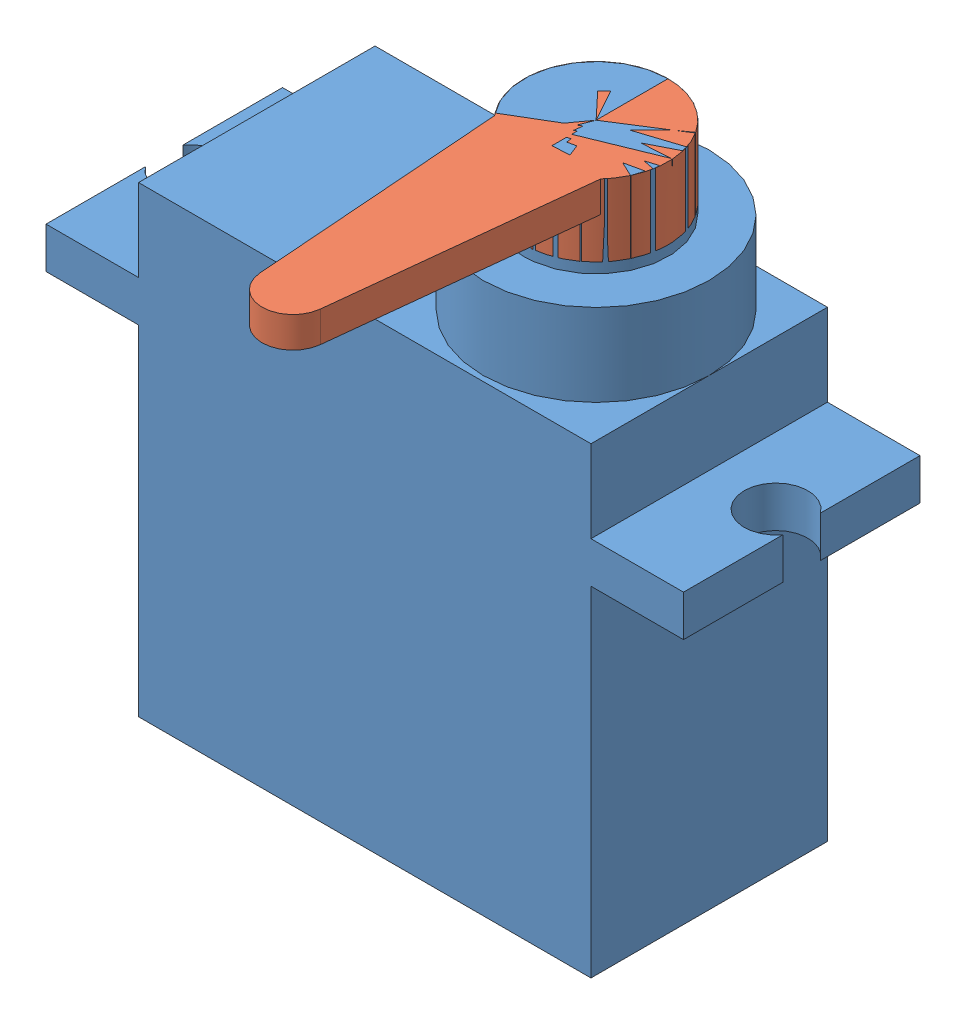
SolidWorks assembly Servo_s, configuration Default. Lengths in mm.
Overall size (31 30.5 21.81).
2 component instances, 2 part files, 2 mates.
Components (placement in the parent):
- Servo_s_Body-1: Servo_s_Body [Default] at (14.7396 6.0253 18.66) size (31 30.5 11.5)
- Servo_s_Wing-1: Servo_s_Wing [Default] at (20.2396 36.5253 18.66) x (0.999858 0 0.016873) z (0 -1 0) size (7 19.5 3.5)
Mates (geometry in assembly coordinates):
- Concentric1: concentric anti-aligned: circle of Servo_s_Body-1; circle of Servo_s_Wing-1
- Coincident2: coincident aligned: plane of Servo_s_Body-1 through (20.2396 36.5253 18.66) normal (0 1 0); plane of Servo_s_Wing-1 through (20.2396 36.5253 18.66) normal (0 1 0)
